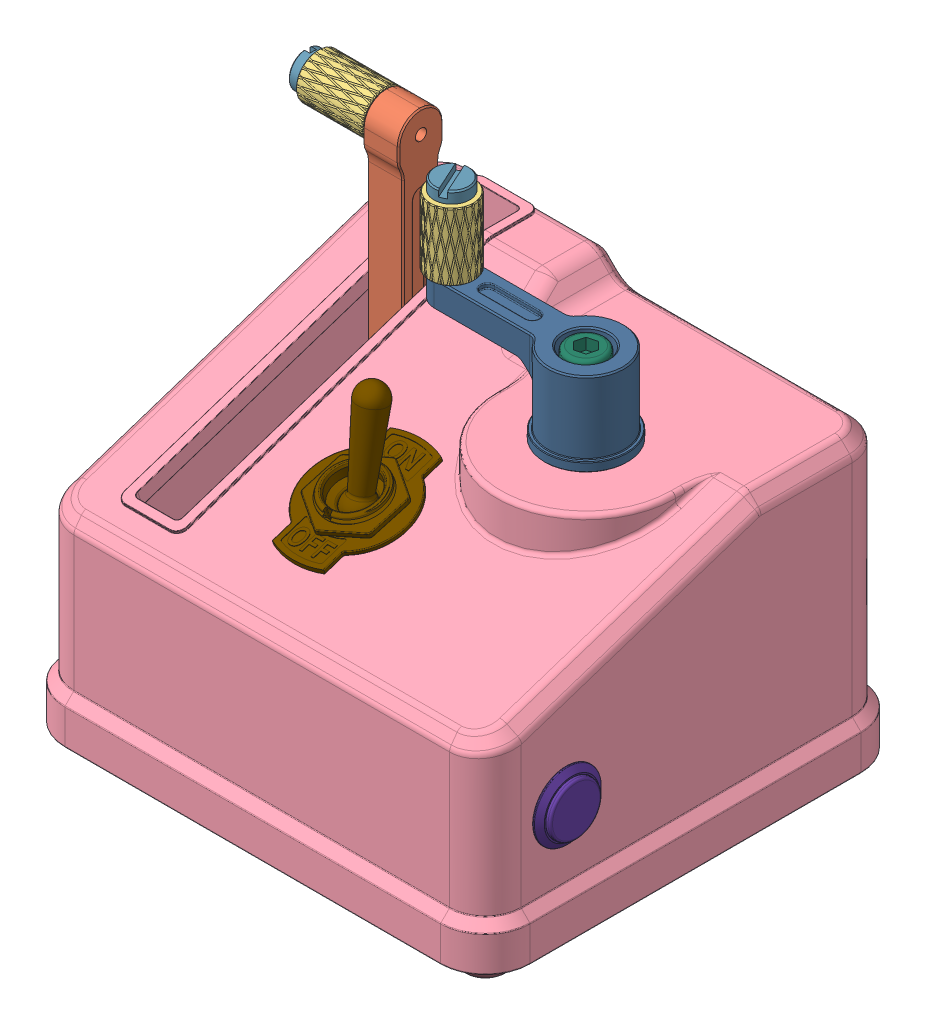
SolidWorks assembly ASF04-10-00, configuration Default. Lengths in mm.
Overall size (105.92 104.62 94).
64 component instances, 31 part files, 126 mates.
Components (placement in the parent):
- ASF04-10-01-2: ASF04-10-01 [Default] at (78.8715 48.4791 91.9509) size (100 8 90)
- ASF04-10-08-3: ASF04-10-08 [Default] at (46.9715 106.4791 73.4509) x (-1 0 0) z (0 0 -1) size (10 87 30)
- ASF04-10-04-1: ASF04-10-04 [Default] at (98.8715 54.4791 106.9509) size (12 25 12)
- ASF04-10-04-2: ASF04-10-04 [Default] at (98.8715 54.4791 61.9509) size (12 25 12)
- ASF04-10-02-2: ASF04-10-02 [Default] at (78.8715 53.4791 91.9509) size (104 68.5 94)
- SPACER M3 M-M H 10mm-1: SPACER M3 M-M H 10mm [Default] at (136.4199 66.4791 151.6284) x (-0.889433 0 -0.457065) z (0 -1 0) size (4.66 5.08 15.26)
- SPACER M3 M-M H 10mm-4: SPACER M3 M-M H 10mm [Default] at (167.4604 66.4791 139.7411) x (-0.967229 0 -0.253905) z (0 -1 0) size (4.66 5.08 15.26)
- ASF03-10-07-1: ASF03-10-07 [Default] at (98.8715 70.0791 84.4509) x (1 0 0) z (0 -1 0) size (15 15 50)
- KFL10-1: KFL10 [Default] at (98.8715 92.2291 84.4509) x (1 0 0) z (0 1 0) size (36 60 15.5)
- BEARING 6700ZZ-2: BEARING 6700ZZ [AFBMA 20.1 - 37-10 - 20,DE,NC,20_68] at (98.8715 106.2291 84.4509) x (0 1 0) z (0.22246 0 0.974942) size (4.5 15 15)
- PAR M3 x 0.5 x 12mm Screw-1: PAR M3 x 0.5 x 12mm Screw [Default] at (111.3715 51.4791 131.9509) x (1 0 0) z (0 -1 0) size (6.06 6.06 13.75)
- ASF04-10-13-1: ASF04-10-13 [Default] at (98.8715 115.0791 84.4509) size (43.3 18 18.6)
- NEODYMIUM 6x4-12: NEODYMIUM 6x4 [Default] at (50.9715 98.4791 73.4509) x (-1 0 0) z (0 0.924257 0.381771) size (4 6 6)
- NEODYMIUM 10x5-1: NEODYMIUM 10x5 [Default] at (98.8715 72.5791 84.4509) x (0 -1 0) z (0.034665 0 0.999399) size (5 10 10)
- C-30-RK-10-1: C-30-RK-10 [Default] at (120.8715 48.4791 128.9509) x (-0.96794 0 0.251182) z (0.251182 0 0.96794) size (10 5 10)
- C-30-RK-10-2: C-30-RK-10 [Default] at (120.8715 48.4791 54.9509) x (-0.319128 0 0.947712) z (0.947712 0 0.319128) size (10 5 10)
- C-30-RK-10-4: C-30-RK-10 [Default] at (36.8715 48.4791 54.9509) x (-0.319128 0 0.947712) z (0.947712 0 0.319128) size (10 5 10)
- C-30-RK-10-6: C-30-RK-10 [Default] at (36.8715 48.4791 128.9509) x (-0.319128 0 0.947712) z (0.947712 0 0.319128) size (10 5 10)
- ASF04-10-06-1: ASF04-10-06 [Default] at (68.8715 145.2791 84.4509) x (0 -1 0) z (0.910389 0 -0.413754) size (22.72 8 8)
- M5x15-1: M5x15 [Default] at (98.8715 125.0791 84.4509) x (-0.964978 0 0.262332) z (0 1 0) size (8.5 8.5 20)
- PAR M3 x 0.5 x 12mm Screw-7: PAR M3 x 0.5 x 12mm Screw [Default] at (111.3715 51.4791 51.9509) x (0.982082 0 -0.188455) z (0 -1 0) size (6.06 6.06 13.75)
- PAR M3 x 0.5 x 12mm Screw-9: PAR M3 x 0.5 x 12mm Screw [Default] at (46.3715 51.4791 131.9509) x (0.918365 0 -0.395734) z (0 -1 0) size (6.06 6.06 13.75)
- PAR M3 x 0.5 x 12mm Screw-11: PAR M3 x 0.5 x 12mm Screw [Default] at (46.3715 51.4791 51.9509) x (0.8 0 -0.6) z (0 -1 0) size (6.06 6.06 13.75)
- PAR M3 x 0.5 x 5mm Screw-8: PAR M3 x 0.5 x 5mm Screw [Default] at (87.8715 68.0791 92.9509) x (0.999106 0 0.042273) z (0 1 0) size (6.06 6.06 6.75)
- PAR M3 x 0.5 x 5mm Screw-14: PAR M3 x 0.5 x 5mm Screw [Default] at (107.3715 68.0791 92.9509) x (0.889141 0 0.457633) z (0 1 0) size (6.06 6.06 6.75)
- LED_MetalButton_12mm-1: LED_MetalButton_12mm [Default] at (128.8715 73.4791 118.9509) x (0 0.381849 -0.924225) z (0 -0.924225 -0.381849) size (18.59 28.56 17.2)
- SPACER M3 M-M H 10mm-7: SPACER M3 M-M H 10mm [Default] at (129.3847 66.4791 118.2493) x (-0.825151 0 -0.564913) z (0 -1 0) size (4.66 5.08 15.26)
- SPACER M3 M-M H 10mm-12: SPACER M3 M-M H 10mm [Default] at (134.3041 66.4791 93.4191) x (-0.99023 0 -0.139447) z (0 -1 0) size (4.66 5.08 15.26)
- PAR M3 x 0.5 x 5mm Screw-16: PAR M3 x 0.5 x 5mm Screw [Default] at (88.5715 68.0791 53.9509) x (0.98516 0 0.171636) z (0 1 0) size (6.06 6.06 6.75)
- PAR M3 x 0.5 x 5mm Screw-18: PAR M3 x 0.5 x 5mm Screw [Default] at (69.1715 68.0791 53.9509) x (0.998997 0 -0.044774) z (0 1 0) size (6.06 6.06 6.75)
- TOGGLE SWITCH-2: TOGGLE SWITCH [Default] at (90.1968 65.4352 81.8696) x (0 -0.312476 0.949926) z (-1 0 0) size (35 53.69 22)
- ASF04-10-09-2: ASF04-10-09 [Default] at (98.8715 79.4791 84.4509) x (0 0 1) z (-1 0 0) size (60 5 26)
- ASF04-10-14-1: ASF04-10-14 [Default] at (98.8715 82.0791 88.4509) x (0 0 1) z (-0.053589 0.998563 0) size (8 3 3)
- ASF04-10-05-3: ASF04-10-05 [Default] at (68.8715 130.0791 84.4509) x (-0.279757 0 0.960071) z (-0.960071 0 -0.279757) size (10.04 15.04 10.04)
- M6 HEX NUT-1: M6 HEX NUT [M6 laag] at (66.9715 74.4791 73.4509) x (0 -0.203574 0.97906) z (0 0.97906 0.203574) size (10 3.32 11.55)
- ASF04-10-03-2: ASF04-10-03 [Default] at (59.4715 79.2291 73.4509) size (12 45.5 55.5)
- BEARING 6700ZZ-4: BEARING 6700ZZ [AFBMA 20.1 - 37-10 - 20,DE,NC,20_68] at (55.7215 74.4791 73.4509) x (-1 0 0) z (0 -0.297764 -0.954639) size (4.5 15 15)
- BEARING 6700ZZ-5: BEARING 6700ZZ [AFBMA 20.1 - 37-10 - 20,DE,NC,20_68] at (63.2215 74.4791 73.4509) x (1 0 0) z (0 -0.700916 -0.713244) size (4.5 15 15)
- ASF04-10-12-2: ASF04-10-12 [Default] at (42.9715 74.4791 73.4509) x (0 0 -1) z (-1 0 0) size (30 30 27.71)
- NEODYMIUM 10x5-3: NEODYMIUM 10x5 [Default] at (45.4715 74.4791 73.4509) x (1 0 0) z (0 0.952379 0.304915) size (5 10 10)
- M6 Washer-2: M6 Washer [B18.22M - Plain washer, 6 mm, narrow] at (65.9715 74.4791 73.4509) x (-1 0 0) z (0 -0.408182 0.912901) size (1 13 13)
- NEODYMIUM 6x4-21: NEODYMIUM 6x4 [Default] at (55.4715 97.0317 65.2424) x (-1 0 0) z (0 0.954274 0.298932) size (4 6 6)
- NEODYMIUM 6x4-22: NEODYMIUM 6x4 [Default] at (55.4715 98.4791 73.4509) x (-1 0 0) z (0 0.644901 0.764266) size (4 6 6)
- NEODYMIUM 6x4-24: NEODYMIUM 6x4 [Default] at (55.4715 97.0317 81.6594) x (-1 0 0) z (0 0.50239 0.864641) size (4 6 6)
- NEODYMIUM 6x4-26: NEODYMIUM 6x4 [Default] at (55.4715 92.8641 88.8778) x (-1 0 0) z (0 0.344614 0.938744) size (4 6 6)
- NEODYMIUM 6x4-28: NEODYMIUM 6x4 [Default] at (55.4715 86.4791 94.2355) x (-1 0 0) z (0 0.176368 0.984324) size (4 6 6)
- SPACER M3 M-M H 12mm-14: SPACER M3 M-M H 12mm [Default] at (41.4715 88.9416 -17.7775) x (0 0.377245 0.926114) z (1 0 0) size (4.66 5.08 17.76)
- SPACER M3 M-M H 12mm-17: SPACER M3 M-M H 12mm [Default] at (41.4715 117.3907 42.565) x (0 -0.405809 0.913958) z (1 0 0) size (4.66 5.08 17.76)
- SPACER M3 M-M H 12mm-19: SPACER M3 M-M H 12mm [Default] at (41.4715 121.9763 11.9942) x (0 -0.489235 0.872152) z (1 0 0) size (4.66 5.08 17.76)
- PCB C-5: PCB C [Default] at (38.6215 74.4791 73.4509) x (0 0 -1) z (1 0 0) size (44 34 2.95)
- PAR M3 x 0.5 x 5mm Screw-30: PAR M3 x 0.5 x 5mm Screw [Default] at (39.3715 61.5653 94.3678) x (0 -0.371154 0.928571) z (-1 0 0) size (6.06 6.06 6.75)
- PAR M3 x 0.5 x 5mm Screw-32: PAR M3 x 0.5 x 5mm Screw [Default] at (39.3715 61.5653 58.3678) x (0 -0.48637 0.873753) z (-1 0 0) size (6.06 6.06 6.75)
- PAR M3 x 0.5 x 5mm Screw-34: PAR M3 x 0.5 x 5mm Screw [Default] at (39.3715 87.5653 58.3678) x (0 -0.565697 0.824613) z (-1 0 0) size (6.06 6.06 6.75)
- ASF04-10-05-4: ASF04-10-05 [Default] at (42.9715 141.4791 73.4509) x (0 0.404344 -0.914607) z (0 0.914607 0.404344) size (10.04 15.04 10.04)
- ASF04-10-06-2: ASF04-10-06 [Default] at (27.7715 141.4791 73.4509) x (1 0 0) z (0 0.03477 0.999395) size (22.72 8 8)
- TMPS B18.3.1M - M3 x 0.5 x 5 Hex-1: TMPS B18.3.1M - M3 x 0.5 x 5 Hex [B18.3.1M - 3 x 0.5 x 16 Hex SHCS -- 16NHX] at (42.9715 74.4791 62.4509) x (1 0 0) z (0 0.010189 0.999948) size (8 5.5 5.5)
- TMPS B18.3.1M - M3 x 0.5 x 5 Hex-2: TMPS B18.3.1M - M3 x 0.5 x 5 Hex [B18.3.1M - 3 x 0.5 x 16 Hex SHCS -- 16NHX] at (42.9715 85.4791 73.4509) x (1 0 0) z (0 -0.148484 0.988915) size (8 5.5 5.5)
- TMPS B18.3.1M - M3 x 0.5 x 5 Hex-4: TMPS B18.3.1M - M3 x 0.5 x 5 Hex [B18.3.1M - 3 x 0.5 x 16 Hex SHCS -- 16NHX] at (42.9715 74.4791 84.4509) x (1 0 0) z (0 -0.273196 0.961958) size (8 5.5 5.5)
- TMPS B18.3.1M - M3 x 0.5 x 5 Hex-6: TMPS B18.3.1M - M3 x 0.5 x 5 Hex [B18.3.1M - 3 x 0.5 x 16 Hex SHCS -- 16NHX] at (42.9715 63.4791 73.4509) x (1 0 0) z (0 -0.361673 0.932305) size (8 5.5 5.5)
- B18.3.1 M6 x 1.0 x 40-1: B18.3.1 M6 x 1.0 x 40 [B18.3.1M - 6 x 1.0 x 120 Hex SHCS -- 24SHX] at (98.8715 95.9791 106.9509) x (0 -1 0) z (0 0 1) size (46 10 10)
- B18.3.1 M6 x 1.0 x 40-2: B18.3.1 M6 x 1.0 x 40 [B18.3.1M - 6 x 1.0 x 120 Hex SHCS -- 24SHX] at (98.8715 95.9791 61.9509) x (0 -1 0) z (0.188455 0 0.982082) size (46 10 10)
- PHS B18.3.1M - M4 x 0.7 x 10 Hex-1: PHS B18.3.1M - M4 x 0.7 x 10 Hex [Default] at (59.4715 52.4791 105.9509) x (0 1 0) z (0 0 1) size (14 7 7)
- PHS B18.3.1M - M4 x 0.7 x 10 Hex-2: PHS B18.3.1M - M4 x 0.7 x 10 Hex [Default] at (59.4715 52.4791 63.4509) x (0 1 0) z (0.188455 0 0.982082) size (14 7 7)
- PCB E-1: PCB E [Default] at (74.4983 43.9059 36.6836) size (45.2 4.85 47.7)
Mates (geometry in assembly coordinates):
- Concentric22: concentric anti-aligned: cylinder of ASF04-10-01-2 through (98.8715 54.4791 106.9509) axis (0 1 0) radius 6.1; cylinder of ASF04-10-04-1 through (98.8715 79.4791 106.9509) axis (0 -1 0) radius 6
- Concentric23: concentric anti-aligned: cylinder of ASF04-10-01-2 through (98.8715 54.4791 61.9509) axis (0 1 0) radius 6.1; cylinder of ASF04-10-04-2 through (98.8715 79.4791 61.9509) axis (0 -1 0) radius 6
- Coincident13: coincident anti-aligned: plane of ASF04-10-01-2 through (98.8715 54.4791 61.9509) normal (0 1 0); plane of ASF04-10-04-2 through (98.8715 54.4791 61.9509) normal (0 -1 0)
- Coincident15: coincident anti-aligned: plane of ASF04-10-01-2 through (98.8715 54.4791 106.9509) normal (0 1 0); plane of ASF04-10-04-1 through (98.8715 54.4791 106.9509) normal (0 -1 0)
- Width1: width anti-aligned: plane of ASF04-10-02-2 through (128.8715 121.4791 46.9509) normal (1 0 0); plane of ASF04-10-01-2 through (28.8715 121.4791 46.9509) normal (-1 0 0); plane of ASF04-10-02-2 through (28.8715 56.4791 46.9509) normal (-1 0 0); plane of ASF04-10-01-2 through (128.8715 56.4791 46.9509) normal (1 0 0)
- Width2: width anti-aligned: plane of ASF04-10-01-2 through (28.8715 56.4791 46.9509) normal (0 0 -1); plane of ASF04-10-02-2 through (28.8715 56.4791 136.9509) normal (0 0 1); plane of ASF04-10-01-2 through (28.8715 121.4791 136.9509) normal (0 0 1); plane of ASF04-10-02-2 through (28.8715 121.4791 46.9509) normal (0 0 -1)
- Coincident18: coincident anti-aligned: plane of ASF04-10-01-2 through (78.8715 53.4791 91.9509) normal (0 1 0); plane of ASF04-10-02-2 through (78.8715 53.4791 91.9509) normal (0 -1 0)
- Coincident35: coincident anti-aligned: plane of ASF04-10-01-2 through (78.8715 56.4791 91.9509) normal (0 1 0); plane of SPACER M3 M-M H 10mm-1 through (84.3085 56.4791 94.095) normal (0 -1 0)
- Concentric44: concentric anti-aligned: cylinder of ASF03-10-07-1 through (98.8715 70.0791 84.4509) axis (0 -1 0) radius 5; cylinder of KFL10-1 through (98.8715 84.4791 84.4509) axis (0 1 0) radius 5
- Concentric45: concentric anti-aligned: cylinder of ASF04-10-04-1 through (98.8715 79.4791 106.9509) axis (0 -1 0) radius 6; cylinder of KFL10-1 through (98.8715 84.4791 106.9509) axis (0 1 0) radius 3.5
- Concentric46: concentric anti-aligned: cylinder of ASF04-10-04-2 through (98.8715 79.4791 61.9509) axis (0 -1 0) radius 6; cylinder of KFL10-1 through (98.8715 84.4791 61.9509) axis (0 1 0) radius 3.5
- Concentric47: concentric anti-aligned: cylinder of ASF03-10-07-1 through (98.8715 70.0791 84.4509) axis (0 -1 0) radius 5; cylinder of BEARING 6700ZZ-2 through (98.8715 85.5916 84.4509) axis (0 1 0) radius 5
- Coincident39: coincident anti-aligned: plane of ASF04-10-02-2 through (56.8715 108.4791 76.1509) normal (0 -1 0); plane of BEARING 6700ZZ-2 through (91.6569 108.4791 86.0971) normal (0 1 0)
- Concentric67: concentric aligned: cylinder of ASF04-10-08-3 through (48.9715 98.4791 73.4509) axis (1 0 0) radius 3; cylinder of NEODYMIUM 6x4-12 through (48.9715 98.4791 73.4509) axis (1 0 0) radius 3
- Coincident461: coincident anti-aligned: plane of ASF04-10-08-3 through (48.9715 98.4791 73.4509) normal (1 0 0); plane of NEODYMIUM 6x4-12 through (48.9715 98.4791 73.4509) normal (-1 0 0)
- Concentric68: concentric anti-aligned: cylinder of ASF03-10-07-1 through (98.8715 75.0791 84.4509) axis (0 -1 0) radius 5; cylinder of NEODYMIUM 10x5-1 through (98.8715 70.0791 84.4509) axis (0 1 0) radius 5
- Coincident462: coincident anti-aligned: plane of ASF03-10-07-1 through (98.8715 75.0791 84.4509) normal (0 -1 0); plane of NEODYMIUM 10x5-1 through (98.8715 75.0791 84.4509) normal (0 1 0)
- Concentric70: concentric aligned: cylinder of ASF04-10-01-2 through (120.8715 56.4791 128.9509) axis (0 -1 0) radius 8; cylinder of C-30-RK-10-1 through (120.8715 48.4791 128.9509) axis (0 -1 0) radius 5
- Coincident464: coincident anti-aligned: plane of ASF04-10-01-2 through (78.8715 48.4791 91.9509) normal (0 -1 0); plane of C-30-RK-10-1 through (119.4196 48.4791 129.3276) normal (0 1 0)
- Concentric72: concentric anti-aligned: cylinder of ASF04-10-01-2 through (120.8715 56.4791 54.9509) axis (0 1 0) radius 1.25; cylinder of C-30-RK-10-2 through (120.8715 48.4791 54.9509) axis (0 -1 0) radius 5
- Coincident465: coincident anti-aligned: plane of ASF04-10-01-2 through (78.8715 48.4791 91.9509) normal (0 -1 0); plane of C-30-RK-10-2 through (120.3928 48.4791 56.3724) normal (0 1 0)
- Concentric73: concentric anti-aligned: cylinder of ASF04-10-01-2 through (36.8715 56.4791 54.9509) axis (0 1 0) radius 1.25; cylinder of C-30-RK-10-4 through (36.8715 48.4791 54.9509) axis (0 -1 0) radius 5
- Coincident466: coincident anti-aligned: plane of ASF04-10-01-2 through (78.8715 48.4791 91.9509) normal (0 -1 0); plane of C-30-RK-10-4 through (36.3928 48.4791 56.3724) normal (0 1 0)
- Concentric74: concentric anti-aligned: cylinder of ASF04-10-01-2 through (36.8715 56.4791 128.9509) axis (0 1 0) radius 1.25; cylinder of C-30-RK-10-6 through (36.8715 48.4791 128.9509) axis (0 -1 0) radius 5
- Coincident467: coincident anti-aligned: plane of ASF04-10-01-2 through (78.8715 48.4791 91.9509) normal (0 -1 0); plane of C-30-RK-10-6 through (36.3928 48.4791 130.3724) normal (0 1 0)
- Concentric80: concentric aligned: cylinder of ASF04-10-13-1 through (98.8715 130.0791 84.4509) axis (0 1 0) radius 2.75; cylinder of M5x15-1 through (98.8715 115.3291 84.4509) axis (0 1 0) radius 2.5
- Coincident472: coincident anti-aligned: plane of ASF04-10-13-1 through (101.6215 125.0791 84.4509) normal (0 1 0); plane of M5x15-1 through (97.7563 125.0791 80.3488) normal (0 -1 0)
- Concentric82: concentric aligned: cylinder of ASF04-10-01-2 through (111.3715 48.4791 131.9509) axis (0 -1 0) radius 1.7; cylinder of PAR M3 x 12mm Screw-1 through (111.3715 63.4791 131.9509) axis (0 -1 0) radius 1.5
- Coincident475: coincident anti-aligned: plane of ASF04-10-01-2 through (113.0715 51.4791 131.9509) normal (0 -1 0); plane of PAR M3 x 12mm Screw-1 through (111.3715 51.4791 131.9509) normal (0 1 0)
- Concentric83: concentric aligned: cylinder of ASF04-10-01-2 through (111.3715 48.4791 51.9509) axis (0 -1 0) radius 1.7; cylinder of PAR M3 x 12mm Screw-7 through (111.3715 63.4791 51.9509) axis (0 -1 0) radius 1.5
- Coincident476: coincident anti-aligned: plane of ASF04-10-01-2 through (113.0715 51.4791 51.9509) normal (0 -1 0); plane of PAR M3 x 12mm Screw-7 through (111.3715 51.4791 51.9509) normal (0 1 0)
- Concentric84: concentric aligned: cylinder of ASF04-10-01-2 through (46.3715 48.4791 131.9509) axis (0 -1 0) radius 1.7; cylinder of PAR M3 x 12mm Screw-9 through (46.3715 63.4791 131.9509) axis (0 -1 0) radius 1.5
- Coincident477: coincident anti-aligned: plane of ASF04-10-01-2 through (48.0715 51.4791 131.9509) normal (0 -1 0); plane of PAR M3 x 12mm Screw-9 through (46.3715 51.4791 131.9509) normal (0 1 0)
- Concentric85: concentric aligned: cylinder of ASF04-10-01-2 through (46.3715 48.4791 51.9509) axis (0 -1 0) radius 1.7; cylinder of PAR M3 x 12mm Screw-11 through (46.3715 63.4791 51.9509) axis (0 -1 0) radius 1.5
- Coincident478: coincident anti-aligned: plane of ASF04-10-01-2 through (48.0715 51.4791 51.9509) normal (0 -1 0); plane of PAR M3 x 12mm Screw-11 through (46.3715 51.4791 51.9509) normal (0 1 0)
- Concentric95: concentric aligned: cylinder of ASF04-10-02-2 through (26.8705 73.4791 118.9509) axis (1 0 0) radius 6.05; cylinder of LED_MetalButton_12mm-1 through (115.8315 73.4791 118.9509) axis (1 0 0) radius 6
- Coincident488: coincident anti-aligned: plane of ASF04-10-02-2 through (128.8715 121.4791 46.9509) normal (1 0 0); plane of LED_MetalButton_12mm-1 through (128.8715 73.4791 118.9509) normal (-1 0 0)
- Coincident493: coincident anti-aligned: plane of ASF04-10-01-2 through (78.8715 56.4791 91.9509) normal (0 1 0); plane of SPACER M3 M-M H 10mm-7 through (84.8932 56.4791 54.6395) normal (0 -1 0)
- Parallel14: parallel aligned: plane of ASF04-10-02-2 through (28.8715 121.4791 136.9509) normal (0 0 1); plane of ASF04-10-13-1 through (98.8715 124.0791 88.4509) normal (0 0 1)
- Concentric113: concentric anti-aligned: cylinder of ASF04-10-02-2 through (73.9594 34.0777 88.727) axis (0 0.949926 0.312476) radius 6.75; cylinder of TOGGLE SWITCH-2 through (73.9594 103.9883 111.7239) axis (0 -0.949926 -0.312476) radius 5
- Coincident512: coincident anti-aligned: plane of ASF04-10-02-2 through (28.8715 116.4791 60.9509) normal (0 0.949926 0.312476); plane of TOGGLE SWITCH-2 through (73.9594 100.1886 110.474) normal (0 -0.949926 -0.312476)
- Parallel15: parallel aligned: plane of ASF04-10-02-2 through (128.8715 121.4791 46.9509) normal (1 0 0); plane of TOGGLE SWITCH-2 through (79.7594 98.1322 119.9255) normal (1 0 0)
- Concentric114: concentric aligned: cylinder of ASF03-10-07-1 through (98.8715 82.0791 91.9509) axis (0 0 -1) radius 1.5; cylinder of ASF04-10-14-1 through (98.8715 82.0791 92.4509) axis (0 0 -1) radius 1.5
- Coincident515: coincident anti-aligned: plane of ASF03-10-07-1 through (98.8715 82.0791 84.4509) normal (0 0 1); plane of ASF04-10-14-1 through (98.8715 82.0791 84.4509) normal (0 0 -1)
- Concentric119: concentric aligned: cylinder of ASF04-10-13-1 through (68.8715 130.0791 84.4509) axis (0 1 0) radius 1.25; cylinder of ASF04-10-05-3 through (68.8715 145.0791 84.4509) axis (0 1 0) radius 2.6
- Coincident524: coincident anti-aligned: plane of ASF04-10-13-1 through (98.8715 130.0791 84.4509) normal (0 1 0); plane of ASF04-10-05-3 through (68.8715 130.0791 84.4509) normal (0 -1 0)
- Concentric120: concentric aligned: cylinder of ASF04-10-13-1 through (68.8715 130.0791 84.4509) axis (0 1 0) radius 1.25; cylinder of ASF04-10-06-1 through (68.8715 127.0791 84.4509) axis (0 1 0) radius 1.5
- Coincident525: coincident anti-aligned: plane of ASF04-10-13-1 through (98.8715 130.0791 84.4509) normal (0 1 0); plane of ASF04-10-06-1 through (67.8371 130.0791 82.1749) normal (0 -1 0)
- Coincident526: coincident anti-aligned: plane of ASF03-10-07-1 through (98.8715 120.0791 84.4509) normal (0 1 0); plane of ASF04-10-13-1 through (98.8715 120.0791 84.4509) normal (0 -1 0)
- Parallel18: parallel aligned: plane of ASF04-10-01-2 through (28.8715 56.4791 136.9509) normal (0 0 1); plane of ASF03-10-07-1 through (89.225 76.0791 83.4509) normal (0 0 1)
- Concentric1292: concentric anti-aligned: cylinder of ASF04-10-01-2 through (107.3715 56.4791 92.9509) axis (0 1 0) radius 1.25; cylinder of PAR M3 x 0.5 x 5mm Screw-14 through (107.3715 69.7291 92.9509) axis (0 -1 0) radius 2.875
- Coincident5484: coincident anti-aligned: plane of ASF04-10-01-2 through (78.8715 56.4791 91.9509) normal (0 1 0); plane of ASF04-10-03-2 through (65.4715 56.4791 100.9509) normal (0 -1 0)
- Concentric1312: concentric aligned: cylinder of ASF04-10-03-2 through (57.9715 74.4791 73.4509) axis (-1 0 0) radius 7.5; cylinder of BEARING 6700ZZ-4 through (76.359 74.4791 73.4509) axis (-1 0 0) radius 5
- Coincident5500: coincident anti-aligned: plane of ASF04-10-03-2 through (57.9715 74.4791 73.4509) normal (-1 0 0); plane of BEARING 6700ZZ-4 through (57.9715 80.9229 71.441) normal (1 0 0)
- Concentric1314: concentric aligned: cylinder of BEARING 6700ZZ-4 through (76.359 74.4791 73.4509) axis (-1 0 0) radius 5; cylinder of ASF04-10-12-2 through (42.9715 74.4791 73.4509) axis (-1 0 0) radius 5
- Coincident5502: coincident anti-aligned: plane of BEARING 6700ZZ-4 through (53.4715 79.3477 71.9323) normal (-1 0 0); plane of ASF04-10-12-2 through (53.4715 74.4791 73.4509) normal (1 0 0)
- Concentric1315: concentric aligned: cylinder of ASF04-10-12-2 through (47.9715 74.4791 73.4509) axis (-1 0 0) radius 5; cylinder of NEODYMIUM 10x5-3 through (47.9715 74.4791 73.4509) axis (-1 0 0) radius 5
- Coincident5503: coincident anti-aligned: plane of ASF04-10-12-2 through (47.9715 74.4791 73.4509) normal (-1 0 0); plane of NEODYMIUM 10x5-3 through (47.9715 74.4791 73.4509) normal (1 0 0)
- Concentric1316: concentric anti-aligned: cylinder of ASF04-10-12-2 through (42.9715 74.4791 73.4509) axis (-1 0 0) radius 5; cylinder of M6 Washer-2 through (100.8965 74.4791 73.4509) axis (1 0 0) radius 6.5
- Coincident5504: coincident anti-aligned: plane of ASF04-10-12-2 through (65.9715 69.4791 73.4509) normal (1 0 0); plane of M6 Washer-2 through (65.9715 71.3433 72.0488) normal (-1 0 0)
- Concentric1317: concentric aligned: cylinder of M6-laag-1 through (70.1715 74.4791 73.4509) axis (-1 0 0) radius 2.5; cylinder of ASF04-10-12-2 through (42.9715 74.4791 73.4509) axis (-1 0 0) radius 5
- Coincident5505: coincident anti-aligned: plane of M6-laag-1 through (66.9715 74.4791 73.4509) normal (-1 0 0); plane of M6 Washer-2 through (66.9715 68.5452 70.7977) normal (1 0 0)
- Concentric1321: concentric aligned: cylinder of ASF04-10-03-2 through (53.4715 97.0317 65.2424) axis (1 0 0) radius 1.5; cylinder of NEODYMIUM 6x4-21 through (53.4715 97.0317 65.2424) axis (1 0 0) radius 3
- Coincident5511: coincident anti-aligned: plane of ASF04-10-03-2 through (57.4715 97.0317 65.2424) normal (-1 0 0); plane of NEODYMIUM 6x4-21 through (57.4715 97.0317 65.2424) normal (1 0 0)
- Concentric1322: concentric anti-aligned: cylinder of ASF04-10-03-2 through (57.4715 98.4791 73.4509) axis (-1 0 0) radius 3; cylinder of NEODYMIUM 6x4-22 through (53.4715 98.4791 73.4509) axis (1 0 0) radius 3
- Coincident5512: coincident anti-aligned: plane of ASF04-10-03-2 through (57.4715 98.4791 73.4509) normal (-1 0 0); plane of NEODYMIUM 6x4-22 through (57.4715 98.4791 73.4509) normal (1 0 0)
- Concentric1323: concentric anti-aligned: cylinder of ASF04-10-03-2 through (57.4715 97.0317 81.6594) axis (-1 0 0) radius 3; cylinder of NEODYMIUM 6x4-24 through (53.4715 97.0317 81.6594) axis (1 0 0) radius 3
- Coincident5513: coincident anti-aligned: plane of ASF04-10-03-2 through (57.4715 97.0317 81.6594) normal (-1 0 0); plane of NEODYMIUM 6x4-24 through (57.4715 97.0317 81.6594) normal (1 0 0)
- Concentric1324: concentric anti-aligned: cylinder of ASF04-10-03-2 through (57.4715 92.8641 88.8778) axis (-1 0 0) radius 3; cylinder of NEODYMIUM 6x4-26 through (53.4715 92.8641 88.8778) axis (1 0 0) radius 3
- Coincident5514: coincident anti-aligned: plane of ASF04-10-03-2 through (57.4715 92.8641 88.8778) normal (-1 0 0); plane of NEODYMIUM 6x4-26 through (57.4715 92.8641 88.8778) normal (1 0 0)
- Concentric1325: concentric anti-aligned: cylinder of ASF04-10-03-2 through (57.4715 86.4791 94.2355) axis (-1 0 0) radius 3; cylinder of NEODYMIUM 6x4-28 through (53.4715 86.4791 94.2355) axis (1 0 0) radius 3
- Coincident5515: coincident anti-aligned: plane of ASF04-10-03-2 through (57.4715 86.4791 94.2355) normal (-1 0 0); plane of NEODYMIUM 6x4-28 through (57.4715 86.4791 94.2355) normal (1 0 0)
- Coincident5516: coincident anti-aligned: plane of ASF04-10-03-2 through (53.4715 79.2291 73.4509) normal (-1 0 0); plane of SPACER M3 M-M H 12mm-14 through (53.4715 91.0141 59.8202) normal (1 0 0)
- Coincident5518: coincident anti-aligned: plane of ASF04-10-03-2 through (53.4715 79.2291 73.4509) normal (-1 0 0); plane of SPACER M3 M-M H 12mm-17 through (53.4715 62.9099 97.8601) normal (1 0 0)
- Coincident5519: coincident anti-aligned: plane of ASF04-10-03-2 through (53.4715 79.2291 73.4509) normal (-1 0 0); plane of SPACER M3 M-M H 12mm-19 through (53.4715 62.5785 61.9702) normal (1 0 0)
- Concentric1331: concentric anti-aligned: cylinder of SPACER M3 M-M H 12mm-19 through (41.4715 61.5653 58.3678) axis (-1 0 0) radius 1.25; cylinder of PCB C-5 through (40.9715 61.5653 58.3678) axis (1 0 0) radius 1.7
- Concentric1333: concentric anti-aligned: cylinder of PCB C-5 through (40.9715 61.5653 94.3678) axis (1 0 0) radius 1.7; cylinder of PAR M3 x 0.5 x 5mm Screw-30 through (51.3715 61.5653 94.3678) axis (-1 0 0) radius 1.5
- Coincident5522: coincident anti-aligned: plane of PCB C-5 through (39.3715 74.5653 73.3678) normal (-1 0 0); plane of PAR M3 x 0.5 x 5mm Screw-30 through (39.3715 61.5653 94.3678) normal (1 0 0)
- Concentric1334: concentric anti-aligned: cylinder of PCB C-5 through (40.9715 61.5653 58.3678) axis (1 0 0) radius 1.7; cylinder of PAR M3 x 0.5 x 5mm Screw-32 through (51.3715 61.5653 58.3678) axis (-1 0 0) radius 1.5
- Coincident5523: coincident anti-aligned: plane of PCB C-5 through (39.3715 74.5653 73.3678) normal (-1 0 0); plane of PAR M3 x 0.5 x 5mm Screw-32 through (39.3715 61.5653 58.3678) normal (1 0 0)
- Concentric1335: concentric anti-aligned: cylinder of PCB C-5 through (40.9715 87.5653 58.3678) axis (1 0 0) radius 1.7; cylinder of PAR M3 x 0.5 x 5mm Screw-34 through (51.3715 87.5653 58.3678) axis (-1 0 0) radius 1.5
- Coincident5524: coincident anti-aligned: plane of PCB C-5 through (39.3715 74.5653 73.3678) normal (-1 0 0); plane of PAR M3 x 0.5 x 5mm Screw-34 through (39.3715 87.5653 58.3678) normal (1 0 0)
- Distance11: distance = 10.5 mm aligned: plane of PCB C-5 through (39.3715 74.5653 73.3678) normal (-1 0 0); plane of ASF04-10-01-2 through (28.8715 56.4791 46.9509) normal (-1 0 0)
- Concentric1340: concentric aligned: cylinder of ASF04-10-03-2 through (60.9715 74.4791 73.4509) axis (1 0 0) radius 7.5; cylinder of BEARING 6700ZZ-5 through (42.584 74.4791 73.4509) axis (1 0 0) radius 7.5
- Coincident5530: coincident anti-aligned: plane of ASF04-10-03-2 through (60.9715 74.4791 73.4509) normal (1 0 0); plane of BEARING 6700ZZ-5 through (60.9715 69.6647 78.1821) normal (-1 0 0)
- Parallel22: parallel aligned: plane of ASF04-10-01-2 through (28.8715 56.4791 136.9509) normal (0 0 1); plane of ASF04-10-08-3 through (50.9715 82.4791 77.4509) normal (0 0 1)
- Concentric1341: concentric aligned: cylinder of ASF04-10-08-3 through (50.9715 74.4791 73.4509) axis (-1 0 0) radius 7.1; cylinder of ASF04-10-12-2 through (47.9715 74.4791 73.4509) axis (-1 0 0) radius 7
- Coincident5533: coincident anti-aligned: plane of ASF04-10-08-3 through (47.9715 74.4791 73.4509) normal (1 0 0); plane of ASF04-10-12-2 through (47.9715 74.4791 73.4509) normal (-1 0 0)
- Concentric1342: concentric aligned: cylinder of ASF04-10-08-3 through (42.9715 85.4791 73.4509) axis (-1 0 0) radius 1.7; cylinder of ASF04-10-12-2 through (47.9715 85.4791 73.4509) axis (-1 0 0) radius 1.25
- Concentric1343: concentric aligned: cylinder of SPACER M3 M-M H 12mm-14 through (41.4715 87.5653 58.3678) axis (-1 0 0) radius 1.25; cylinder of PAR M3 x 0.5 x 5mm Screw-34 through (51.3715 87.5653 58.3678) axis (-1 0 0) radius 1.5
- Concentric1344: concentric aligned: cylinder of SPACER M3 M-M H 12mm-17 through (41.4715 61.5653 94.3678) axis (-1 0 0) radius 1.25; cylinder of PAR M3 x 0.5 x 5mm Screw-30 through (51.3715 61.5653 94.3678) axis (-1 0 0) radius 1.5
- Concentric1345: concentric aligned: cylinder of ASF04-10-12-2 through (42.9715 74.4791 73.4509) axis (-1 0 0) radius 5; cylinder of PCB C-5 through (42.6685 74.4791 73.4509) axis (-1 0 0) radius 0.6
- Parallel23: parallel aligned: plane of ASF04-10-01-2 through (78.8715 56.4791 91.9509) normal (0 1 0); plane of PCB C-5 through (40.9715 91.5653 88.3678) normal (0 1 0)
- Concentric1347: concentric aligned: cylinder of ASF04-10-08-3 through (50.9715 141.4791 73.4509) axis (-1 0 0) radius 5; cylinder of ASF04-10-05-4 through (27.9715 141.4791 73.4509) axis (-1 0 0) radius 2.6
- Coincident5537: coincident anti-aligned: plane of ASF04-10-08-3 through (42.9715 106.4791 73.4509) normal (-1 0 0); plane of ASF04-10-05-4 through (42.9715 141.4791 73.4509) normal (1 0 0)
- Concentric1348: concentric aligned: cylinder of ASF04-10-08-3 through (50.9715 141.4791 73.4509) axis (-1 0 0) radius 5; cylinder of ASF04-10-06-2 through (32.7715 141.4791 73.4509) axis (-1 0 0) radius 2.5
- Coincident5538: coincident anti-aligned: plane of ASF04-10-08-3 through (42.9715 106.4791 73.4509) normal (-1 0 0); plane of ASF04-10-06-2 through (42.9715 143.9776 73.364) normal (1 0 0)
- Concentric1349: concentric anti-aligned: cylinder of ASF04-10-01-2 through (88.5715 56.4791 53.9509) axis (0 1 0) radius 1.25; cylinder of PAR M3 x 0.5 x 5mm Screw-16 through (88.5715 69.7291 53.9509) axis (0 -1 0) radius 2.875
- Concentric1354: concentric aligned: cylinder of ASF04-10-08-3 through (42.9715 74.4791 62.4509) axis (-1 0 0) radius 3.25; cylinder of TMPS B18.3.1M - M3 x 0.5 x 5 Hex-1 through (11.2215 74.4791 62.4509) axis (-1 0 0) radius 1.5
- Coincident5539: coincident anti-aligned: plane of ASF04-10-08-3 through (45.9715 76.1791 62.4509) normal (-1 0 0); plane of TMPS B18.3.1M - M3 x 0.5 x 5 Hex-1 through (45.9715 77.2289 62.4229) normal (1 0 0)
- Concentric1355: concentric aligned: cylinder of ASF04-10-08-3 through (42.9715 85.4791 73.4509) axis (-1 0 0) radius 3.25; cylinder of TMPS B18.3.1M - M3 x 0.5 x 5 Hex-2 through (11.2215 85.4791 73.4509) axis (-1 0 0) radius 1.5
- Coincident5540: coincident anti-aligned: plane of ASF04-10-08-3 through (45.9715 87.1791 73.4509) normal (-1 0 0); plane of TMPS B18.3.1M - M3 x 0.5 x 5 Hex-2 through (45.9715 88.1986 73.8592) normal (1 0 0)
- Concentric1356: concentric aligned: cylinder of ASF04-10-08-3 through (42.9715 74.4791 84.4509) axis (-1 0 0) radius 3.25; cylinder of TMPS B18.3.1M - M3 x 0.5 x 5 Hex-4 through (11.2215 74.4791 84.4509) axis (-1 0 0) radius 1.5
- Coincident5541: coincident anti-aligned: plane of ASF04-10-08-3 through (45.9715 76.1791 84.4509) normal (-1 0 0); plane of TMPS B18.3.1M - M3 x 0.5 x 5 Hex-4 through (45.9715 77.1245 85.2022) normal (1 0 0)
- Concentric1357: concentric aligned: cylinder of ASF04-10-08-3 through (42.9715 63.4791 73.4509) axis (-1 0 0) radius 3.25; cylinder of TMPS B18.3.1M - M3 x 0.5 x 5 Hex-6 through (11.2215 63.4791 73.4509) axis (-1 0 0) radius 1.5
- Coincident5542: coincident anti-aligned: plane of ASF04-10-08-3 through (45.9715 65.1791 73.4509) normal (-1 0 0); plane of TMPS B18.3.1M - M3 x 0.5 x 5 Hex-6 through (45.9715 66.0429 74.4455) normal (1 0 0)
- Concentric1358: concentric anti-aligned: cylinder of ASF04-10-08-3 through (52.9715 94.0964 87.2769) axis (-1 0 0) radius 1.5; cylinder of ASF04-10-03-2 through (53.4715 98.4791 73.4509) axis (1 0 0) radius 1.5
- Concentric1360: concentric aligned: cylinder of ASF04-10-01-2 through (59.4715 48.4791 63.4509) axis (0 -1 0) radius 2.25; cylinder of ASF04-10-03-2 through (59.4715 56.4791 63.4509) axis (0 -1 0) radius 1.65
- Concentric13651: concentric aligned: cylinder of KFL10-1 through (98.8715 84.4791 106.9509) axis (0 1 0) radius 3.5; cylinder of B18.3.1 M6 x 1.0 x 40-1 through (98.8715 127.7291 106.9509) axis (0 1 0) radius 5
- Coincident55471: coincident anti-aligned: plane of KFL10-1 through (98.8715 89.9791 54.4509) normal (0 1 0); plane of B18.3.1 M6 x 1.0 x 40-1 through (103.8715 89.9791 106.9509) normal (0 -1 0)
- Concentric1366: concentric aligned: cylinder of KFL10-1 through (98.8715 84.4791 61.9509) axis (0 1 0) radius 3.5; cylinder of B18.3.1 M6 x 1.0 x 40-2 through (98.8715 127.7291 61.9509) axis (0 1 0) radius 5
- Coincident5548: coincident anti-aligned: plane of KFL10-1 through (98.8715 89.9791 54.4509) normal (0 1 0); plane of B18.3.1 M6 x 1.0 x 40-2 through (103.7819 89.9791 61.0086) normal (0 -1 0)
- Concentric1367: concentric anti-aligned: cylinder of ASF04-10-01-2 through (59.4715 48.4791 105.9509) axis (0 -1 0) radius 2.25; cylinder of CSN 02 1143 - M4 x 15-1 through (59.4715 85.4791 105.9509) axis (0 1 0) radius 2
- Coincident5549: coincident anti-aligned: plane of ASF04-10-01-2 through (61.7215 52.4791 105.9509) normal (0 -1 0); plane of CSN 02 1143 - M4 x 15-1 through (56.7215 52.4791 105.9509) normal (0 1 0)
- Concentric1368: concentric anti-aligned: cylinder of ASF04-10-01-2 through (59.4715 48.4791 63.4509) axis (0 -1 0) radius 2.25; cylinder of CSN 02 1143 - M4 x 15-2 through (59.4715 85.4791 63.4509) axis (0 1 0) radius 2
- Coincident5550: coincident anti-aligned: plane of ASF04-10-01-2 through (61.7215 52.4791 63.4509) normal (0 -1 0); plane of CSN 02 1143 - M4 x 15-2 through (56.7708 52.4791 63.9691) normal (0 1 0)
- Concentric13653: concentric aligned: cylinder of SPACER M3 M-M H 10mm-12 through (69.1715 66.4791 53.9509) axis (0 1 0) radius 1.25; cylinder of PAR M3 x 0.5 x 5mm Screw-18 through (69.1715 56.0791 53.9509) axis (0 1 0) radius 1.5
- Concentric13654: concentric anti-aligned: cylinder of ASF04-10-01-2 through (69.1715 56.4791 53.9509) axis (0 1 0) radius 1.25; cylinder of SPACER M3 M-M H 10mm-12 through (69.1715 56.0541 53.9509) axis (0 -1 0) radius 1.1752
- Coincident55473: coincident anti-aligned: plane of ASF04-10-01-2 through (78.8715 56.4791 91.9509) normal (0 1 0); plane of SPACER M3 M-M H 10mm-12 through (66.1822 56.4791 56.2021) normal (0 -1 0)
- Concentric13657: concentric aligned: cylinder of ASF04-10-09-2 through (98.8715 84.4791 61.9509) axis (0 1 0) radius 3.3; cylinder of B18.3.1 M6 x 1.0 x 40-2 through (98.8715 127.7291 61.9509) axis (0 1 0) radius 3
- Coincident55476: coincident anti-aligned: plane of KFL10-1 through (98.8715 84.4791 68.7009) normal (0 -1 0); plane of ASF04-10-09-2 through (98.8715 84.4791 61.9509) normal (0 1 0)
- Coincident55477: coincident anti-aligned: plane of ASF04-10-04-2 through (98.8715 79.4791 61.9509) normal (0 1 0); plane of ASF04-10-09-2 through (98.8715 79.4791 61.9509) normal (0 -1 0)
- Concentric13658: concentric aligned: cylinder of PAR M3 x 0.5 x 5mm Screw-8 through (87.8715 56.0791 92.9509) axis (0 1 0) radius 1.5; cylinder of PCB E-1 through (87.8715 68.0791 92.9509) axis (0 1 0) radius 1.7
- Concentric13659: concentric aligned: cylinder of PAR M3 x 0.5 x 5mm Screw-14 through (107.3715 56.0791 92.9509) axis (0 1 0) radius 1.5; cylinder of PCB E-1 through (107.3715 68.0791 92.9509) axis (0 1 0) radius 1.7
- Concentric13660: concentric anti-aligned: cylinder of ASF04-10-01-2 through (87.8715 56.4791 92.9509) axis (0 1 0) radius 1.25; cylinder of SPACER M3 M-M H 10mm-1 through (87.8715 56.0541 92.9509) axis (0 -1 0) radius 1.1752
- Concentric13661: concentric aligned: cylinder of ASF04-10-09-2 through (98.8715 84.4791 106.9509) axis (0 1 0) radius 3.3; cylinder of B18.3.1 M6 x 1.0 x 40-1 through (98.8715 127.7291 106.9509) axis (0 1 0) radius 3
